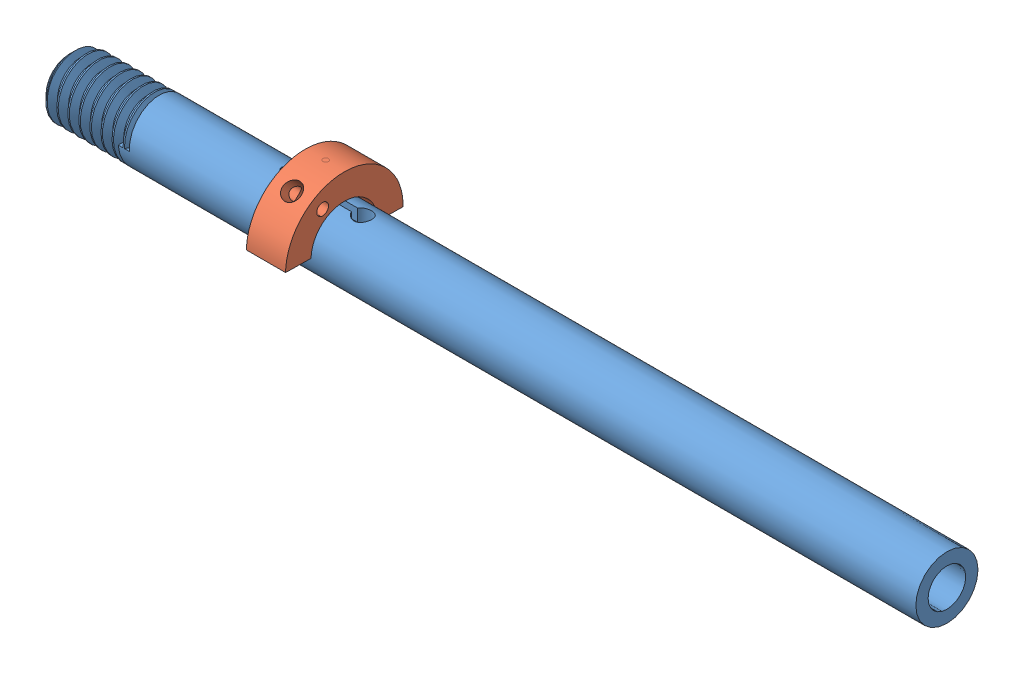
SolidWorks assembly slider assembly v-1 26-Oct-2017, configuration Default. Lengths in mm.
Overall size (112.38 16.84 25.8).
2 component instances, 2 part files, 1 mates.
Components (placement in the parent):
- wheel_handle_body_slider v-1 26-Oct-2017-1: wheel_handle_body_slider v-1 26-Oct-2017 [Default] at (-3.1634 60.0837 85.9698) size (112.38 7.99 8.1)
- slider v-1 26-Oct-2017-1: slider v-1 26-Oct-2017 [Default] at (14.9419 60.0837 85.9698) x (1 0 0) z (0 0.014517 0.999895) size (5 16.47 25.56)
Mates (geometry in assembly coordinates):
- Concentric1: concentric aligned: circle of wheel_handle_body_slider v-1 26-Oct-2017-1; circle of slider v-1 26-Oct-2017-1
